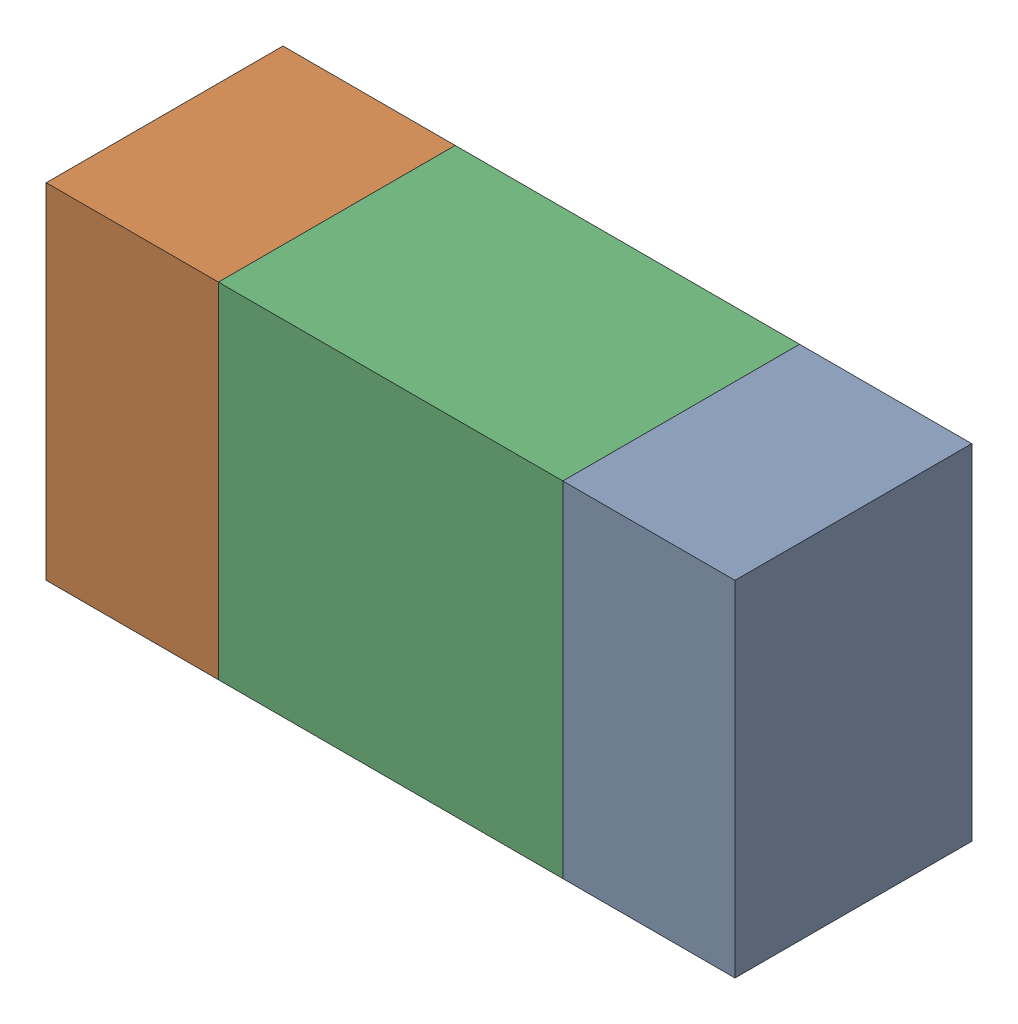
SolidWorks assembly R80, configuration ﾃﾞﾌｫﾙﾄ. Lengths in mm.
Overall size (1.6 0.8 0.55).
6 component instances, 2 part files, 0 mates.
Components (placement in the parent):
- 689261512-1: 689261512 [ﾃﾞﾌｫﾙﾄ] at (23.0999 56.2501 -1.7503) size (0.4 0.8 0.55)
  - Extruded_32-1: Extruded_32 [ﾃﾞﾌｫﾙﾄ] at origin size (0.4 0.8 0.55)
- 689261512-2: 689261512 [ﾃﾞﾌｫﾙﾄ] at (21.8999 56.2501 -1.7503) size (0.4 0.8 0.55)
  - Extruded_32-1: Extruded_32 [ﾃﾞﾌｫﾙﾄ] at origin size (0.4 0.8 0.55)
- 689261648-1: 689261648 [ﾃﾞﾌｫﾙﾄ] at (22.5 56.2501 -1.7503) size (0.8 0.8 0.55)
  - Extruded_33-1: Extruded_33 [ﾃﾞﾌｫﾙﾄ] at origin size (0.8 0.8 0.55)
